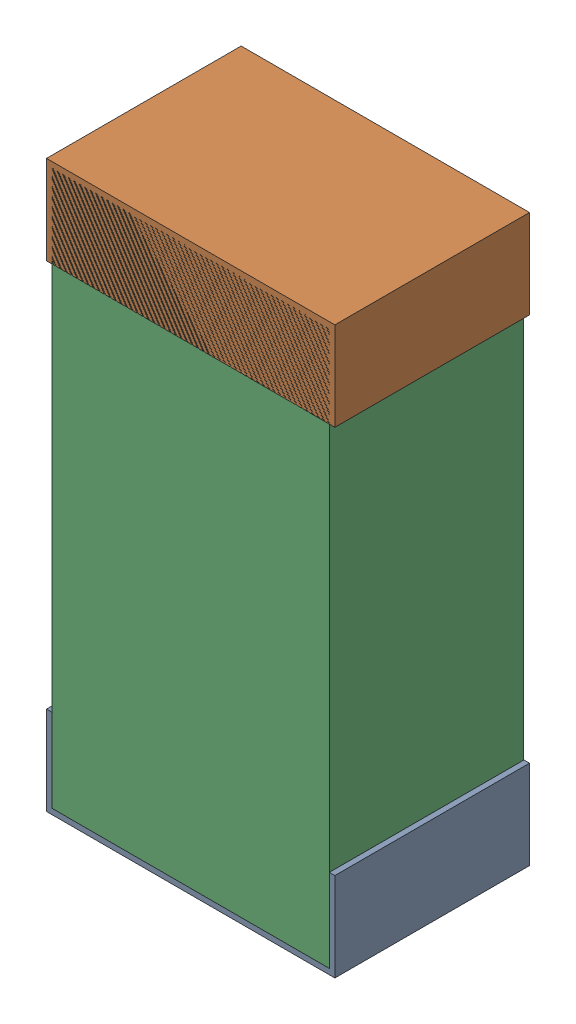
SolidWorks assembly C49, configuration Default. Lengths in mm.
Overall size (0.52 1.02 0.35).
6 component instances, 2 part files, 0 mates.
Components (placement in the parent):
- 870941120-1: 870941120 [Default] at (14.3502 36.8076 -1.9516) size (0.52 0.16 0.35)
  - Extruded_3-1: Extruded_3 [Default] at origin size (0.52 0.16 0.35)
- 870941120-2: 870941120 [Default] at (14.3502 37.6676 -1.9516) size (0.52 0.16 0.35)
  - Extruded_3-1: Extruded_3 [Default] at origin size (0.52 0.16 0.35)
- 870941280-1: 870941280 [Default] at (14.3502 37.2376 -1.9506) size (0.5 1 0.35)
  - Extruded_4-1: Extruded_4 [Default] at origin size (0.5 1 0.35)
